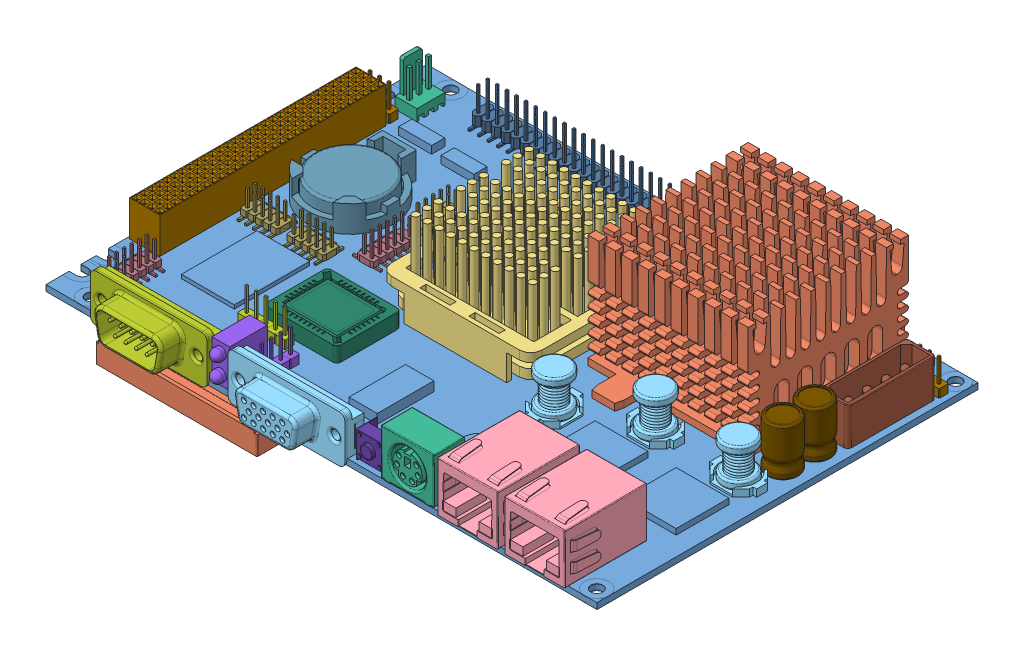
SolidWorks assembly User Library-pc emb ecm-3714 ddm, configuration Default. Lengths in mm.
Overall size (146.04 41.8 107.5).
36 component instances, 27 part files, 103 mates.
Components (placement in the parent):
- User Library-pc emb ecm-3714 ddm_Base CI PC EMB ECM-3714-1: User Library-pc emb ecm-3714 ddm_Base CI PC EMB ECM-3714 [Default] at (-116.1738 3.3292 -30.5336) size (146.04 5.8 101)
- User Library-pc emb ecm-3714 ddm_Disipador aluminio PC DDM-1: User Library-pc emb ecm-3714 ddm_Disipador aluminio PC DDM [Default] at (-2.7838 6.6292 -2.2836) x (0 0 -1) z (1 0 0) size (56.3 30 42.5)
- User Library-pc emb ecm-3714 ddm_Disipador plastico PC DDM-1: User Library-pc emb ecm-3714 ddm_Disipador plastico PC DDM [Default] at (-46.1738 4.9292 11.9664) x (0 0 1) z (-1 0 0) size (40 21.6 41.6)
- User Library-pc emb ecm-3714 ddm_Conector Ethernet PC DDM-1: User Library-pc emb ecm-3714 ddm_Conector Ethernet PC DDM [Default] at (14.6462 5.2292 71.7664) x (-1 0 0) z (0 0 -1) size (18.29 14.35 21.8)
- User Library-pc emb ecm-3714 ddm_Conector Ethernet PC DDM-2: User Library-pc emb ecm-3714 ddm_Conector Ethernet PC DDM [Default] at (-3.1438 5.2292 71.7664) x (-1 0 0) z (0 0 -1) size (18.29 14.35 21.8)
- User Library-pc emb ecm-3714 ddm_Conector VGA PC DDM-1: User Library-pc emb ecm-3714 ddm_Conector VGA PC DDM [Default] at (-51.7338 9.0792 70.6664) size (31 12.5 10.8)
- User Library-pc emb ecm-3714 ddm_Conector raton PC DDM-1: User Library-pc emb ecm-3714 ddm_Conector raton PC DDM [Default] at (-12.6538 5.2292 71.1664) x (-1 0 0) z (0 0 -1) size (14 12.6 8.3)
- User Library-pc emb ecm-3714 ddm_Conector Serial PC DDM-1: User Library-pc emb ecm-3714 ddm_Conector Serial PC DDM [Default] at (-88.2338 9.0792 70.6664) size (31 12.5 10.8)
- User Library-pc emb ecm-3714 ddm_Leds PC DDM-1: User Library-pc emb ecm-3714 ddm_Leds PC DDM [Default] at (-72.2138 4.9292 60.4664) size (4.7 10 12.4)
- User Library-pc emb ecm-3714 ddm_Conector PC104 PCEMB DDM-1: User Library-pc emb ecm-3714 ddm_Conector PC104 PCEMB DDM [Default] at (-115.5338 4.9292 48.9264) size (8 9.5 60)
- User Library-pc emb ecm-3714 ddm_Conector 20x2 PCEMB DDM-1: User Library-pc emb ecm-3714 ddm_Conector 20x2 PCEMB DDM [Default] at (-95.5938 4.9292 -23.0136) size (50.56 9.5 7.5)
- User Library-pc emb ecm-3714 ddm_Conector pwr PCEMB DDM-1: User Library-pc emb ecm-3714 ddm_Conector pwr PCEMB DDM [Default] at (24.0662 3.9292 -9.5836) size (8 10 23.5)
- User Library-pc emb ecm-3714 ddm_Conector 5x2 paso 2 PCEMB DDM-1: User Library-pc emb ecm-3714 ddm_Conector 5x2 paso 2 PCEMB DDM [Default] at (-105.4338 4.9292 28.2764) size (9.9 6.5 7.5)
- User Library-pc emb ecm-3714 ddm_Conector 5x2 paso 2 PCEMB DDM-2: User Library-pc emb ecm-3714 ddm_Conector 5x2 paso 2 PCEMB DDM [Default] at (-93.2438 4.9292 28.1564) size (9.9 6.5 7.5)
- User Library-pc emb ecm-3714 ddm_Conector 5x2 paso 2 PCEMB DDM-3: User Library-pc emb ecm-3714 ddm_Conector 5x2 paso 2 PCEMB DDM [Default] at (-79.3238 4.9292 0.6864) x (0 0 1) z (-1 0 0) size (9.9 6.5 7.5)
- User Library-pc emb ecm-3714 ddm_Conector 6x2 paso 2 PCEMB DDM-1: User Library-pc emb ecm-3714 ddm_Conector 6x2 paso 2 PCEMB DDM [Default] at (-76.8238 4.9292 23.3764) x (0 0 -1) z (1 0 0) size (11.9 6.5 7.5)
- User Library-pc emb ecm-3714 ddm_Conector 6x2 paso 2 PCEMB DDM-2: User Library-pc emb ecm-3714 ddm_Conector 6x2 paso 2 PCEMB DDM [Default] at (-105.5238 4.9292 62.3664) x (0 0 -1) z (1 0 0) size (11.9 6.5 7.5)
- User Library-pc emb ecm-3714 ddm_Pila PCEMB DDM-1: User Library-pc emb ecm-3714 ddm_Pila PCEMB DDM [Default] at (-95.4575 4.9292 10.4664) x (-1 0 0) z (0 0 -1) size (23 7 24.5)
- User Library-pc emb ecm-3714 ddm_Integrado BIOS PCEMB DDM-1: User Library-pc emb ecm-3714 ddm_Integrado BIOS PCEMB DDM [Default] at (-69.0238 4.9292 41.7664) x (0 0 1) z (-1 0 0) size (17 4 19.5)
- User Library-pc emb ecm-3714 ddm_Conector SATA PCEMB DDM-1: User Library-pc emb ecm-3714 ddm_Conector SATA PCEMB DDM [Default] at (-33.1138 4.9292 -27.8036) size (17 8.4 4)
- User Library-pc emb ecm-3714 ddm_Conector SATA PCEMB DDM-2: User Library-pc emb ecm-3714 ddm_Conector SATA PCEMB DDM [Default] at (-15.5838 4.9292 -27.8036) size (17 8.4 4)
- User Library-pc emb ecm-3714 ddm_Pulsador reset PCEMB DDM-1: User Library-pc emb ecm-3714 ddm_Pulsador reset PCEMB DDM [Default] at (-31.3438 8.7792 69.4664) size (7 7.1 6.3)
- User Library-pc emb ecm-3714 ddm_Condensador PCEMB DDM-1: User Library-pc emb ecm-3714 ddm_Condensador PCEMB DDM [Default] at (23.8662 4.9292 6.701) x (0 0 -1) z (1 0 0) size (8.2 12.5 8.2)
- User Library-pc emb ecm-3714 ddm_Condensador PCEMB DDM-2: User Library-pc emb ecm-3714 ddm_Condensador PCEMB DDM [Default] at (23.6726 4.9292 15.0035) size (8.2 12.5 8.2)
- User Library-pc emb ecm-3714 ddm_Conector CF PCEMB DDM-1: User Library-pc emb ecm-3714 ddm_Conector CF PCEMB DDM [Default] at (-78.6338 4.7292 29.4564) x (-1 0 0) z (0 0 1) size (48 8.5 35)
- User Library-pc emb ecm-3714 ddm_Tarjeta compact flash II DDM-1: User Library-pc emb ecm-3714 ddm_Tarjeta compact flash II DDM [Default] at (-78.6338 -1.1708 37.0564) x (-1 0 0) z (0 0 1) size (42.8 5.65 36.4)
- User Library-pc emb ecm-3714 ddm_Conector Memoria RAM DEIDE - 2Rev3DOCDD3-1: User Library-pc emb ecm-3714 ddm_Conector Memoria RAM DEIDE - 2Rev3DOCDD3 [Default] at (-67.4938 3.3292 -13.5336) x (1 0 0) z (0 0 -1) size (71 5.5 9)
- User Library-pc emb ecm-3714 ddm_SODIMM Memoria RAM DDM-1: User Library-pc emb ecm-3714 ddm_SODIMM Memoria RAM DDM [Default] at (-67.6518 -0.2708 18.4664) x (-1 0 0) z (0 0 1) size (67.7 3 31.8)
- User Library-pc emb ecm-3714 ddm_Componente NN PCEMB DDM-1: User Library-pc emb ecm-3714 ddm_Componente NN PCEMB DDM [Default] at (20.6162 4.9292 23.6664) size (12.5 10.7 9.2)
- User Library-pc emb ecm-3714 ddm_Componente NN PCEMB DDM-2: User Library-pc emb ecm-3714 ddm_Componente NN PCEMB DDM [Default] at (-1.3838 4.9292 23.6664) size (12.5 10.7 9.2)
- User Library-pc emb ecm-3714 ddm_Componente NN PCEMB DDM-3: User Library-pc emb ecm-3714 ddm_Componente NN PCEMB DDM [Default] at (-19.4338 4.9292 32.5164) x (0 0 -1) z (1 0 0) size (12.5 10.7 9.2)
- User Library-pc emb ecm-3714 ddm_Conector 3 pins PCEMB DDM-1: User Library-pc emb ecm-3714 ddm_Conector 3 pins PCEMB DDM [Default] at (-104.3838 4.9292 -16.0636) x (0 0 -1) z (1 0 0) size (7.5 11.5 5.8)
- User Library-pc emb ecm-3714 ddm_Conector 5x1 PCEMB DDM-1: User Library-pc emb ecm-3714 ddm_Conector 5x1 PCEMB DDM [Default] at (-81.1938 4.9292 52.7364) size (12.7 8.5 2.54)
- User Library-pc emb ecm-3714 ddm_Conector 4x1 PCEMB DDM-1: User Library-pc emb ecm-3714 ddm_Conector 4x1 PCEMB DDM [Default] at (-65.8738 4.9292 55.9864) x (0 0 1) z (-1 0 0) size (10.16 8.5 2.54)
- User Library-pc emb ecm-3714 ddm_Conector 3x1 PCEMB DDM-1: User Library-pc emb ecm-3714 ddm_Conector 3x1 PCEMB DDM [Default] at (-114.1338 4.9292 -12.8536) size (7.62 8.5 2.54)
- User Library-pc emb ecm-3714 ddm_Conector 3x1 PCEMB DDM-2: User Library-pc emb ecm-3714 ddm_Conector 3x1 PCEMB DDM [Default] at (21.7562 4.9292 -22.7536) size (7.62 8.5 2.54)
Mates (geometry in assembly coordinates):
- Distancia1: distance = 31.7 mm aligned: plane of User Library-pc emb ecm-3714 ddm_Base CI PC EMB ECM-3714-1 through (-114.5338 4.9292 -18.1136) normal (0 1 0); plane of User Library-pc emb ecm-3714 ddm_Disipador aluminio PC DDM-1 through (18.4662 36.6292 18.9664) normal (0 1 0)
- Distancia2: distance = 7 mm aligned: plane of User Library-pc emb ecm-3714 ddm_Base CI PC EMB ECM-3714-1 through (-116.1738 4.9292 -30.5336) normal (0 0 -1); plane of User Library-pc emb ecm-3714 ddm_Disipador aluminio PC DDM-1 through (-24.0338 36.6292 -23.5336) normal (0 0 -1)
- Distancia3: distance = 11.4 mm aligned: plane of User Library-pc emb ecm-3714 ddm_Base CI PC EMB ECM-3714-1 through (29.8662 4.9292 -30.5336) normal (1 0 0); plane of User Library-pc emb ecm-3714 ddm_Disipador aluminio PC DDM-1 through (18.4662 36.6292 18.9664) normal (1 0 0)
- Coincidente1: coincident anti-aligned: plane of User Library-pc emb ecm-3714 ddm_Base CI PC EMB ECM-3714-1 through (-114.5338 4.9292 -18.1136) normal (0 1 0); plane of User Library-pc emb ecm-3714 ddm_Disipador plastico PC DDM-1 through (-66.1838 4.9292 10.2564) normal (0 -1 0)
- Distancia4: distance = 22.5 mm aligned: plane of User Library-pc emb ecm-3714 ddm_Base CI PC EMB ECM-3714-1 through (-116.1738 4.9292 -30.5336) normal (0 0 -1); plane of User Library-pc emb ecm-3714 ddm_Disipador plastico PC DDM-1 through (-26.1738 14.1292 -8.0336) normal (0 0 -1)
- Distancia5: distance = 50 mm aligned: plane of User Library-pc emb ecm-3714 ddm_Base CI PC EMB ECM-3714-1 through (-116.1738 4.9292 -16.5136) normal (-1 0 0); plane of User Library-pc emb ecm-3714 ddm_Disipador plastico PC DDM-1 through (-66.1738 14.1292 -8.0336) normal (-1 0 0)
- Distancia6: distance = 13.5 mm aligned: plane of User Library-pc emb ecm-3714 ddm_Base CI PC EMB ECM-3714-1 through (-114.5338 4.9292 -18.1136) normal (0 1 0); plane of User Library-pc emb ecm-3714 ddm_Conector Ethernet PC DDM-1 through (22.6462 18.4292 49.9664) normal (0 1 0)
- Distancia7: distance = 1.3 mm aligned: plane of User Library-pc emb ecm-3714 ddm_Base CI PC EMB ECM-3714-1 through (-116.1738 4.9292 70.4664) normal (0 0 1); plane of User Library-pc emb ecm-3714 ddm_Conector Ethernet PC DDM-1 through (22.6462 5.2292 71.7664) normal (0 0 1)
- Distancia8: distance = 122.82 mm aligned: plane of User Library-pc emb ecm-3714 ddm_Base CI PC EMB ECM-3714-1 through (-116.1738 4.9292 -30.5336) normal (-1 0 0); plane of User Library-pc emb ecm-3714 ddm_Conector Ethernet PC DDM-1 through (6.6462 18.4292 49.9664) normal (-1 0 0)
- Coincidente7: coincident aligned: plane of User Library-pc emb ecm-3714 ddm_Conector Ethernet PC DDM-1 through (22.6462 5.2292 71.7664) normal (0 0 1); plane of User Library-pc emb ecm-3714 ddm_Conector Ethernet PC DDM-2 through (4.8562 5.2292 71.7664) normal (0 0 1)
- Coincidente8: coincident aligned: plane of User Library-pc emb ecm-3714 ddm_Conector Ethernet PC DDM-1 through (22.6462 18.4292 49.9664) normal (0 1 0); plane of User Library-pc emb ecm-3714 ddm_Conector Ethernet PC DDM-2 through (4.8562 18.4292 49.9664) normal (0 1 0)
- Distancia9: distance = 105.03 mm aligned: plane of User Library-pc emb ecm-3714 ddm_Base CI PC EMB ECM-3714-1 through (-116.1738 4.9292 64.3464) normal (-1 0 0); plane of User Library-pc emb ecm-3714 ddm_Conector Ethernet PC DDM-2 through (-11.1438 18.4292 49.9664) normal (-1 0 0)
- Distancia11: distance = 12 mm anti-aligned: plane of User Library-pc emb ecm-3714 ddm_Base CI PC EMB ECM-3714-1 through (-114.5338 3.3292 -18.1136) normal (0 -1 0); plane of User Library-pc emb ecm-3714 ddm_Conector VGA PC DDM-1 through (-37.7338 15.3292 66.1664) normal (0 1 0)
- Distancia12: distance = 0.2 mm anti-aligned: plane of User Library-pc emb ecm-3714 ddm_Base CI PC EMB ECM-3714-1 through (-116.1738 4.9292 70.4664) normal (0 0 1); plane of User Library-pc emb ecm-3714 ddm_Conector VGA PC DDM-1 through (-67.2338 2.8292 70.6664) normal (0 0 -1)
- Distancia13: distance = 48.94 mm aligned: plane of User Library-pc emb ecm-3714 ddm_Base CI PC EMB ECM-3714-1 through (-116.1738 4.9292 64.3464) normal (-1 0 0); plane of User Library-pc emb ecm-3714 ddm_Conector VGA PC DDM-1 through (-67.2338 13.8292 66.1664) normal (-1 0 0)
- Distancia14: distance = 14.5 mm anti-aligned: plane of User Library-pc emb ecm-3714 ddm_Base CI PC EMB ECM-3714-1 through (-114.5338 3.3292 -18.1136) normal (0 -1 0); plane of User Library-pc emb ecm-3714 ddm_Conector raton PC DDM-1 through (-12.6538 17.8292 62.8664) normal (0 1 0)
- Coincidente15: coincident aligned: plane of User Library-pc emb ecm-3714 ddm_Conector VGA PC DDM-1 through (-67.2338 2.8292 71.1664) normal (0 0 1); plane of User Library-pc emb ecm-3714 ddm_Conector raton PC DDM-1 through (-12.6538 17.8292 71.1664) normal (0 0 1)
- Distancia15: distance = 89.52 mm aligned: plane of User Library-pc emb ecm-3714 ddm_Base CI PC EMB ECM-3714-1 through (-116.1738 4.9292 64.3464) normal (-1 0 0); plane of User Library-pc emb ecm-3714 ddm_Conector raton PC DDM-1 through (-26.6538 5.2292 62.8664) normal (-1 0 0)
- Coincidente17: coincident aligned: plane of User Library-pc emb ecm-3714 ddm_Conector VGA PC DDM-1 through (-37.7338 15.3292 66.1664) normal (0 1 0); plane of User Library-pc emb ecm-3714 ddm_Conector Serial PC DDM-1 through (-74.2338 15.3292 66.1664) normal (0 1 0)
- Coincidente18: coincident aligned: plane of User Library-pc emb ecm-3714 ddm_Conector VGA PC DDM-1 through (-67.2338 2.8292 71.1664) normal (0 0 1); plane of User Library-pc emb ecm-3714 ddm_Conector Serial PC DDM-1 through (-103.7338 2.8292 71.1664) normal (0 0 1)
- Distancia16: distance = 12.44 mm aligned: plane of User Library-pc emb ecm-3714 ddm_Base CI PC EMB ECM-3714-1 through (-116.1738 4.9292 64.3464) normal (-1 0 0); plane of User Library-pc emb ecm-3714 ddm_Conector Serial PC DDM-1 through (-103.7338 13.8292 66.1664) normal (-1 0 0)
- Distancia17: distance = 11.6 mm anti-aligned: plane of User Library-pc emb ecm-3714 ddm_Leds PC DDM-1 through (-72.2138 14.9292 70.4664) normal (0 1 0); plane of User Library-pc emb ecm-3714 ddm_Base CI PC EMB ECM-3714-1 through (-114.5338 3.3292 -18.1136) normal (0 -1 0)
- Coincidente21: coincident aligned: plane of User Library-pc emb ecm-3714 ddm_Base CI PC EMB ECM-3714-1 through (-116.1738 4.9292 70.4664) normal (0 0 1); plane of User Library-pc emb ecm-3714 ddm_Leds PC DDM-1 through (-72.2138 14.9292 70.4664) normal (0 0 1)
- Distancia18: distance = 43.96 mm aligned: plane of User Library-pc emb ecm-3714 ddm_Base CI PC EMB ECM-3714-1 through (-116.1738 4.9292 64.3464) normal (-1 0 0); plane of User Library-pc emb ecm-3714 ddm_Leds PC DDM-1 through (-72.2138 4.9292 70.4664) normal (-1 0 0)
- Distancia19: distance = 78.46 mm anti-aligned: plane of User Library-pc emb ecm-3714 ddm_Base CI PC EMB ECM-3714-1 through (-116.1738 4.9292 -30.5336) normal (0 0 -1); plane of User Library-pc emb ecm-3714 ddm_Conector PC104 PCEMB DDM-1 through (-115.5338 4.9292 47.9264) normal (0 0 1)
- Distancia20: distance = 7.64 mm anti-aligned: plane of User Library-pc emb ecm-3714 ddm_Base CI PC EMB ECM-3714-1 through (-116.1738 4.9292 -16.5136) normal (-1 0 0); plane of User Library-pc emb ecm-3714 ddm_Conector PC104 PCEMB DDM-1 through (-108.5338 4.9292 48.9264) normal (1 0 0)
- Coincidente25: coincident anti-aligned: plane of User Library-pc emb ecm-3714 ddm_Base CI PC EMB ECM-3714-1 through (-114.5338 4.9292 -18.1136) normal (0 1 0); plane of User Library-pc emb ecm-3714 ddm_Conector PC104 PCEMB DDM-1 through (-115.5338 4.9292 -11.0736) normal (0 -1 0)
- Distancia23: distance = 69.34 mm anti-aligned: plane of User Library-pc emb ecm-3714 ddm_Base CI PC EMB ECM-3714-1 through (-116.1738 4.9292 -30.5336) normal (-1 0 0); plane of User Library-pc emb ecm-3714 ddm_Conector 20x2 PCEMB DDM-1 through (-46.8338 14.4292 -23.0136) normal (1 0 0)
- Distancia24: distance = 4.48 mm aligned: plane of User Library-pc emb ecm-3714 ddm_Base CI PC EMB ECM-3714-1 through (-116.1738 4.9292 -30.5336) normal (0 0 -1); plane of User Library-pc emb ecm-3714 ddm_Conector 20x2 PCEMB DDM-1 through (-47.3338 14.4292 -26.0536) normal (0 0 -1)
- Coincidente31: coincident anti-aligned: plane of User Library-pc emb ecm-3714 ddm_Base CI PC EMB ECM-3714-1 through (-114.5338 4.9292 -18.1136) normal (0 1 0); plane of User Library-pc emb ecm-3714 ddm_Conector 20x2 PCEMB DDM-1 through (-95.5938 4.9292 -23.5136) normal (0 -1 0)
- Coincidente32: coincident anti-aligned: plane of User Library-pc emb ecm-3714 ddm_Base CI PC EMB ECM-3714-1 through (-114.5338 4.9292 -18.1136) normal (0 1 0); plane of User Library-pc emb ecm-3714 ddm_Conector pwr PCEMB DDM-1 through (21.0662 4.9292 1.1664) normal (0 -1 0)
- Distancia25: distance = 1.8 mm aligned: plane of User Library-pc emb ecm-3714 ddm_Base CI PC EMB ECM-3714-1 through (29.8662 4.9292 -30.5336) normal (1 0 0); plane of User Library-pc emb ecm-3714 ddm_Conector pwr PCEMB DDM-1 through (28.0662 5.4292 -20.3336) normal (1 0 0)
- Distancia26: distance = 9.2 mm aligned: plane of User Library-pc emb ecm-3714 ddm_Base CI PC EMB ECM-3714-1 through (-116.1738 4.9292 -30.5336) normal (0 0 -1); plane of User Library-pc emb ecm-3714 ddm_Conector pwr PCEMB DDM-1 through (21.0662 5.4292 -21.3336) normal (0 0 -1)
- Distancia27: distance = 10.74 mm aligned: plane of User Library-pc emb ecm-3714 ddm_Base CI PC EMB ECM-3714-1 through (-116.1738 4.9292 -16.5136) normal (-1 0 0); plane of User Library-pc emb ecm-3714 ddm_Conector 5x2 paso 2 PCEMB DDM-1 through (-105.4338 11.4292 28.2764) normal (-1 0 0)
- Distancia28: distance = 58.81 mm anti-aligned: plane of User Library-pc emb ecm-3714 ddm_Base CI PC EMB ECM-3714-1 through (-116.1738 4.9292 -30.5336) normal (0 0 -1); plane of User Library-pc emb ecm-3714 ddm_Conector 5x2 paso 2 PCEMB DDM-1 through (-105.4338 11.4292 28.2764) normal (0 0 1)
- Coincidente37: coincident anti-aligned: plane of User Library-pc emb ecm-3714 ddm_Base CI PC EMB ECM-3714-1 through (-114.5338 4.9292 -18.1136) normal (0 1 0); plane of User Library-pc emb ecm-3714 ddm_Conector 5x2 paso 2 PCEMB DDM-1 through (-97.4338 4.9292 27.7764) normal (0 -1 0)
- Distancia29: distance = 22.93 mm aligned: plane of User Library-pc emb ecm-3714 ddm_Base CI PC EMB ECM-3714-1 through (-116.1738 4.9292 -16.5136) normal (-1 0 0); plane of User Library-pc emb ecm-3714 ddm_Conector 5x2 paso 2 PCEMB DDM-2 through (-93.2438 11.4292 28.1564) normal (-1 0 0)
- Distancia30: distance = 58.69 mm anti-aligned: plane of User Library-pc emb ecm-3714 ddm_Base CI PC EMB ECM-3714-1 through (-116.1738 4.9292 -30.5336) normal (0 0 -1); plane of User Library-pc emb ecm-3714 ddm_Conector 5x2 paso 2 PCEMB DDM-2 through (-93.2438 11.4292 28.1564) normal (0 0 1)
- Coincidente40: coincident anti-aligned: plane of User Library-pc emb ecm-3714 ddm_Base CI PC EMB ECM-3714-1 through (-114.5338 4.9292 -18.1136) normal (0 1 0); plane of User Library-pc emb ecm-3714 ddm_Conector 5x2 paso 2 PCEMB DDM-2 through (-93.2438 4.9292 27.6564) normal (0 -1 0)
- Distancia31: distance = 36.85 mm aligned: plane of User Library-pc emb ecm-3714 ddm_Base CI PC EMB ECM-3714-1 through (-116.1738 4.9292 -16.5136) normal (-1 0 0); plane of User Library-pc emb ecm-3714 ddm_Conector 5x2 paso 2 PCEMB DDM-3 through (-79.3238 11.4292 0.6864) normal (-1 0 0)
- Distancia32: distance = 31.22 mm aligned: plane of User Library-pc emb ecm-3714 ddm_Base CI PC EMB ECM-3714-1 through (-116.1738 4.9292 -30.5336) normal (0 0 -1); plane of User Library-pc emb ecm-3714 ddm_Conector 5x2 paso 2 PCEMB DDM-3 through (-79.3238 11.4292 0.6864) normal (0 0 -1)
- Coincidente43: coincident anti-aligned: plane of User Library-pc emb ecm-3714 ddm_Base CI PC EMB ECM-3714-1 through (-114.5338 4.9292 -18.1136) normal (0 1 0); plane of User Library-pc emb ecm-3714 ddm_Conector 5x2 paso 2 PCEMB DDM-3 through (-78.8238 4.9292 6.6864) normal (0 -1 0)
- Coincidente44: coincident aligned: plane of User Library-pc emb ecm-3714 ddm_Conector 5x2 paso 2 PCEMB DDM-3 through (-75.9238 6.9292 9.672) normal (1 0 0); plane of User Library-pc emb ecm-3714 ddm_Conector 6x2 paso 2 PCEMB DDM-1 through (-75.9238 6.9292 14.3907) normal (1 0 0)
- Coincidente45: coincident aligned: plane of User Library-pc emb ecm-3714 ddm_Conector 5x2 paso 2 PCEMB DDM-3 through (-80.2238 6.9292 7.0486) normal (0 1 0); plane of User Library-pc emb ecm-3714 ddm_Conector 6x2 paso 2 PCEMB DDM-1 through (-75.9238 6.9292 15.0142) normal (0 1 0)
- Distancia33: distance = 43.41 mm aligned: plane of User Library-pc emb ecm-3714 ddm_Base CI PC EMB ECM-3714-1 through (-116.1738 4.9292 -30.5336) normal (0 0 -1); plane of User Library-pc emb ecm-3714 ddm_Conector 6x2 paso 2 PCEMB DDM-1 through (-74.5738 5.4292 12.8764) normal (0 0 -1)
- Distancia34: distance = 10.65 mm anti-aligned: plane of User Library-pc emb ecm-3714 ddm_Base CI PC EMB ECM-3714-1 through (-116.1738 4.9292 64.3464) normal (-1 0 0); plane of User Library-pc emb ecm-3714 ddm_Conector 6x2 paso 2 PCEMB DDM-2 through (-105.5238 11.4292 62.3664) normal (1 0 0)
- Coincidente48: coincident anti-aligned: plane of User Library-pc emb ecm-3714 ddm_Base CI PC EMB ECM-3714-1 through (-114.5338 4.9292 -18.1136) normal (0 1 0); plane of User Library-pc emb ecm-3714 ddm_Conector 6x2 paso 2 PCEMB DDM-2 through (-106.0238 4.9292 62.3664) normal (0 -1 0)
- Distancia35: distance = 7.4 mm aligned: plane of User Library-pc emb ecm-3714 ddm_Base CI PC EMB ECM-3714-1 through (-116.1738 4.9292 70.4664) normal (0 0 1); plane of User Library-pc emb ecm-3714 ddm_Conector 6x2 paso 2 PCEMB DDM-2 through (-108.1238 6.9292 63.0664) normal (0 0 1)
- Coincidente50: coincident anti-aligned: plane of User Library-pc emb ecm-3714 ddm_Base CI PC EMB ECM-3714-1 through (-114.5338 4.9292 -18.1136) normal (0 1 0); plane of User Library-pc emb ecm-3714 ddm_Pila PCEMB DDM-1 through (-95.4575 4.9292 10.4664) normal (0 -1 0)
- Distancia36: distance = 28 mm aligned: plane of User Library-pc emb ecm-3714 ddm_Base CI PC EMB ECM-3714-1 through (-116.1738 4.9292 -30.5336) normal (0 0 -1); plane of User Library-pc emb ecm-3714 ddm_Pila PCEMB DDM-1 through (-99.9575 11.9292 -2.5336) normal (0 0 -1)
- Distancia37: distance = 26.1566 mm aligned: plane of User Library-pc emb ecm-3714 ddm_Base CI PC EMB ECM-3714-1 through (-116.1738 4.9292 -16.5136) normal (-1 0 0); plane of User Library-pc emb ecm-3714 ddm_Pila PCEMB DDM-1 through (-90.0172 7.9292 16.2445) normal (-1 0 0)
- Distancia38: distance = 20.2 mm aligned: plane of User Library-pc emb ecm-3714 ddm_Base CI PC EMB ECM-3714-1 through (-116.1738 4.9292 70.4664) normal (0 0 1); plane of User Library-pc emb ecm-3714 ddm_Integrado BIOS PCEMB DDM-1 through (-60.2738 8.9292 50.2664) normal (0 0 1)
- Distancia39: distance = 37.4 mm aligned: plane of User Library-pc emb ecm-3714 ddm_Base CI PC EMB ECM-3714-1 through (-116.1738 4.9292 -16.5136) normal (-1 0 0); plane of User Library-pc emb ecm-3714 ddm_Integrado BIOS PCEMB DDM-1 through (-78.7738 8.9292 34.2664) normal (-1 0 0)
- Coincidente55: coincident anti-aligned: plane of User Library-pc emb ecm-3714 ddm_Base CI PC EMB ECM-3714-1 through (-114.5338 4.9292 -18.1136) normal (0 1 0); plane of User Library-pc emb ecm-3714 ddm_Integrado BIOS PCEMB DDM-1 through (-60.2738 4.9292 34.2664) normal (0 -1 0)
- Distancia40: distance = 4.73 mm anti-aligned: plane of User Library-pc emb ecm-3714 ddm_Base CI PC EMB ECM-3714-1 through (-116.1738 4.9292 -30.5336) normal (0 0 -1); plane of User Library-pc emb ecm-3714 ddm_Conector SATA PCEMB DDM-1 through (-41.6138 13.3292 -25.8036) normal (0 0 1)
- Distancia41: distance = 74.56 mm aligned: plane of User Library-pc emb ecm-3714 ddm_Base CI PC EMB ECM-3714-1 through (-116.1738 4.9292 -30.5336) normal (-1 0 0); plane of User Library-pc emb ecm-3714 ddm_Conector SATA PCEMB DDM-1 through (-41.6138 13.3292 -29.8036) normal (-1 0 0)
- Coincidente58: coincident anti-aligned: plane of User Library-pc emb ecm-3714 ddm_Base CI PC EMB ECM-3714-1 through (-114.5338 4.9292 -18.1136) normal (0 1 0); plane of User Library-pc emb ecm-3714 ddm_Conector SATA PCEMB DDM-1 through (-41.6138 4.9292 -25.8036) normal (0 -1 0)
- Coincidente59: coincident aligned: plane of User Library-pc emb ecm-3714 ddm_Conector SATA PCEMB DDM-1 through (-41.6138 13.3292 -25.8036) normal (0 0 1); plane of User Library-pc emb ecm-3714 ddm_Conector SATA PCEMB DDM-2 through (-24.0838 13.3292 -25.8036) normal (0 0 1)
- Distancia42: distance = 92.09 mm aligned: plane of User Library-pc emb ecm-3714 ddm_Base CI PC EMB ECM-3714-1 through (-116.1738 4.9292 -30.5336) normal (-1 0 0); plane of User Library-pc emb ecm-3714 ddm_Conector SATA PCEMB DDM-2 through (-24.0838 13.3292 -29.8036) normal (-1 0 0)
- Coincidente61: coincident anti-aligned: plane of User Library-pc emb ecm-3714 ddm_Base CI PC EMB ECM-3714-1 through (-114.5338 4.9292 -18.1136) normal (0 1 0); plane of User Library-pc emb ecm-3714 ddm_Conector SATA PCEMB DDM-2 through (-24.0838 4.9292 -25.8036) normal (0 -1 0)
- Coincidente62: coincident anti-aligned: plane of User Library-pc emb ecm-3714 ddm_Base CI PC EMB ECM-3714-1 through (-114.5338 4.9292 -18.1136) normal (0 1 0); plane of User Library-pc emb ecm-3714 ddm_Pulsador reset PCEMB DDM-1 through (-28.0438 4.9292 64.1664) normal (0 -1 0)
- Distancia43: distance = 81.33 mm aligned: plane of User Library-pc emb ecm-3714 ddm_Base CI PC EMB ECM-3714-1 through (-116.1738 4.9292 64.3464) normal (-1 0 0); plane of User Library-pc emb ecm-3714 ddm_Pulsador reset PCEMB DDM-1 through (-34.8438 12.0292 69.6664) normal (-1 0 0)
- Coincidente64: coincident aligned: plane of User Library-pc emb ecm-3714 ddm_Base CI PC EMB ECM-3714-1 through (-116.1738 4.9292 70.4664) normal (0 0 1); plane of User Library-pc emb ecm-3714 ddm_Pulsador reset PCEMB DDM-1 through (-31.3438 8.7792 70.4664) normal (0 0 1)
- Coincidente65: coincident anti-aligned: plane of User Library-pc emb ecm-3714 ddm_Base CI PC EMB ECM-3714-1 through (-114.5338 4.9292 -18.1136) normal (0 1 0); plane of User Library-pc emb ecm-3714 ddm_Condensador PCEMB DDM-1 through (23.8662 4.9292 6.701) normal (0 -1 0)
- Distancia44: distance = 6 mm aligned: plane of User Library-pc emb ecm-3714 ddm_Base CI PC EMB ECM-3714-1 through (29.8662 4.9292 -30.5336) normal (1 0 0); plane of User Library-pc emb ecm-3714 ddm_Condensador PCEMB DDM-1 through (23.8662 4.9292 6.701) normal (1 0 0)
- Distancia45: distance = 37.2346 mm aligned: plane of User Library-pc emb ecm-3714 ddm_Base CI PC EMB ECM-3714-1 through (-116.1738 4.9292 -30.5336) normal (0 0 -1); plane of User Library-pc emb ecm-3714 ddm_Condensador PCEMB DDM-1 through (23.8662 4.9292 6.701) normal (0 0 -1)
- Coincidente68: coincident aligned: plane of User Library-pc emb ecm-3714 ddm_Condensador PCEMB DDM-1 through (23.8662 17.2292 6.701) normal (0 1 0); plane of User Library-pc emb ecm-3714 ddm_Condensador PCEMB DDM-2 through (23.6726 17.2292 15.0035) normal (0 1 0)
- Coincidente69: coincident anti-aligned: plane of User Library-pc emb ecm-3714 ddm_Base CI PC EMB ECM-3714-1 through (-114.5338 3.3292 -18.1136) normal (0 -1 0); plane of User Library-pc emb ecm-3714 ddm_Conector CF PCEMB DDM-1 through (-44.6338 3.3292 25.0912) normal (0 1 0)
- Concéntrica1: concentric aligned: circle of User Library-pc emb ecm-3714 ddm_Base CI PC EMB ECM-3714-1; circle of User Library-pc emb ecm-3714 ddm_Conector CF PCEMB DDM-1
- Concéntrica2: concentric aligned: circle of User Library-pc emb ecm-3714 ddm_Base CI PC EMB ECM-3714-1; circle of User Library-pc emb ecm-3714 ddm_Conector CF PCEMB DDM-1
- Coincidente72: coincident anti-aligned: plane of User Library-pc emb ecm-3714 ddm_Conector CF PCEMB DDM-1 through (-94.7338 33.1595 37.0564) normal (0 0 1); plane of User Library-pc emb ecm-3714 ddm_Tarjeta compact flash II DDM-1 through (-57.2338 1.3292 37.0564) normal (0 0 -1)
- Distancia47: distance = 0.2 mm anti-aligned: plane of User Library-pc emb ecm-3714 ddm_Conector CF PCEMB DDM-1 through (-58.0338 -5.1708 64.4564) normal (-1 0 0); plane of User Library-pc emb ecm-3714 ddm_Tarjeta compact flash II DDM-1 through (-58.2338 -1.9208 63.0564) normal (1 0 0)
- Coincidente76: coincident anti-aligned: plane of User Library-pc emb ecm-3714 ddm_Conector CF PCEMB DDM-1 through (-100.2338 -1.9208 36.6564) normal (0 -1 0); plane of User Library-pc emb ecm-3714 ddm_Tarjeta compact flash II DDM-1 through (-100.5798 -1.9208 63.0564) normal (0 1 0)
- Coincidente77: coincident anti-aligned: plane of User Library-pc emb ecm-3714 ddm_Base CI PC EMB ECM-3714-1 through (-114.5338 3.3292 -18.1136) normal (0 -1 0); plane of User Library-pc emb ecm-3714 ddm_Conector Memoria RAM DEIDE - 2Rev3DOCDD3-1 through (-102.9938 3.3292 -17.0336) normal (0 1 0)
- Distancia48: distance = 20.5 mm anti-aligned: plane of User Library-pc emb ecm-3714 ddm_Base CI PC EMB ECM-3714-1 through (-116.1738 4.9292 -30.5336) normal (0 0 -1); plane of User Library-pc emb ecm-3714 ddm_Conector Memoria RAM DEIDE - 2Rev3DOCDD3-1 through (-102.9938 -2.1708 -10.0336) normal (0 0 1)
- Distancia49: distance = 48.68 mm anti-aligned: plane of User Library-pc emb ecm-3714 ddm_Base CI PC EMB ECM-3714-1 through (-116.1738 4.9292 -30.5336) normal (-1 0 0); plane of User Library-pc emb ecm-3714 ddm_Conector Memoria RAM DEIDE - 2Rev3DOCDD3-1
- Distancia50: distance = 5.6 mm aligned: plane of User Library-pc emb ecm-3714 ddm_Base CI PC EMB ECM-3714-1 through (-114.5338 3.3292 -18.1136) normal (0 -1 0); plane of User Library-pc emb ecm-3714 ddm_SODIMM Memoria RAM DDM-1 through (-50.1518 -2.2708 16.4664) normal (0 -1 0)
- Distancia51: distance = 52 mm aligned: plane of User Library-pc emb ecm-3714 ddm_Base CI PC EMB ECM-3714-1 through (-116.1738 4.9292 70.4664) normal (0 0 1); plane of User Library-pc emb ecm-3714 ddm_SODIMM Memoria RAM DDM-1 through (-33.8018 -1.2708 18.4664) normal (0 0 1)
- Distancia52: distance = 14.672 mm aligned: plane of User Library-pc emb ecm-3714 ddm_Base CI PC EMB ECM-3714-1 through (-116.1738 4.9292 -16.5136) normal (-1 0 0); plane of User Library-pc emb ecm-3714 ddm_SODIMM Memoria RAM DDM-1 through (-101.5018 -1.2708 -13.3336) normal (-1 0 0)
- Distancia53: distance = 0.1 mm anti-aligned: plane of User Library-pc emb ecm-3714 ddm_Disipador aluminio PC DDM-1 through (-24.0338 36.6292 18.9664) normal (0 0 1); plane of User Library-pc emb ecm-3714 ddm_Componente NN PCEMB DDM-1 through (15.3662 6.8292 19.0664) normal (0 0 -1)
- Coincidente84: coincident anti-aligned: plane of User Library-pc emb ecm-3714 ddm_Base CI PC EMB ECM-3714-1 through (-114.5338 4.9292 -18.1136) normal (0 1 0); plane of User Library-pc emb ecm-3714 ddm_Componente NN PCEMB DDM-1 through (15.3662 4.9292 28.2664) normal (0 -1 0)
- Distancia54: distance = 3 mm aligned: plane of User Library-pc emb ecm-3714 ddm_Base CI PC EMB ECM-3714-1 through (29.8662 4.9292 -30.5336) normal (1 0 0); plane of User Library-pc emb ecm-3714 ddm_Componente NN PCEMB DDM-1 through (26.8662 4.9292 22.2164) normal (1 0 0)
- Coincidente86: coincident aligned: plane of User Library-pc emb ecm-3714 ddm_Componente NN PCEMB DDM-1 through (20.6162 15.6292 23.6664) normal (0 1 0); plane of User Library-pc emb ecm-3714 ddm_Componente NN PCEMB DDM-2 through (-1.3838 15.6292 23.6664) normal (0 1 0)
- Coincidente87: coincident aligned: plane of User Library-pc emb ecm-3714 ddm_Componente NN PCEMB DDM-1 through (15.3662 6.8292 28.2664) normal (0 0 1); plane of User Library-pc emb ecm-3714 ddm_Componente NN PCEMB DDM-2 through (-6.6338 6.8292 28.2664) normal (0 0 1)
- Distancia55: distance = 9.5 mm anti-aligned: plane of User Library-pc emb ecm-3714 ddm_Componente NN PCEMB DDM-1 through (14.3662 4.9292 22.2164) normal (-1 0 0); plane of User Library-pc emb ecm-3714 ddm_Componente NN PCEMB DDM-2 through (4.8662 4.9292 22.2164) normal (1 0 0)
- Coincidente89: coincident aligned: plane of User Library-pc emb ecm-3714 ddm_Componente NN PCEMB DDM-2 through (-1.3838 15.6292 23.6664) normal (0 1 0); plane of User Library-pc emb ecm-3714 ddm_Componente NN PCEMB DDM-3 through (-19.4338 15.6292 32.5164) normal (0 1 0)
- Distancia56: distance = 33 mm aligned: plane of User Library-pc emb ecm-3714 ddm_Conector Ethernet PC DDM-2 through (4.8562 5.2292 71.7664) normal (0 0 1); plane of User Library-pc emb ecm-3714 ddm_Componente NN PCEMB DDM-3 through (-20.8838 4.9292 38.7664) normal (0 0 1)
- Coincidente91: coincident aligned: plane of User Library-pc emb ecm-3714 ddm_Disipador aluminio PC DDM-1 through (-24.0338 36.6292 18.9664) normal (-1 0 0); plane of User Library-pc emb ecm-3714 ddm_Componente NN PCEMB DDM-3 through (-24.0338 6.8292 37.7664) normal (-1 0 0)
- Distancia57: distance = 7.78 mm aligned: plane of User Library-pc emb ecm-3714 ddm_Base CI PC EMB ECM-3714-1 through (-116.1738 4.9292 -30.5336) normal (0 0 -1); plane of User Library-pc emb ecm-3714 ddm_Conector 3 pins PCEMB DDM-1 through (-107.9838 15.4292 -22.7536) normal (0 0 -1)
- Distancia58: distance = 8.19 mm aligned: plane of User Library-pc emb ecm-3714 ddm_Base CI PC EMB ECM-3714-1 through (-116.1738 4.9292 -30.5336) normal (-1 0 0); plane of User Library-pc emb ecm-3714 ddm_Conector 3 pins PCEMB DDM-1 through (-107.9838 15.4292 -21.9536) normal (-1 0 0)
- Coincidente94: coincident anti-aligned: plane of User Library-pc emb ecm-3714 ddm_Base CI PC EMB ECM-3714-1 through (-114.5338 4.9292 -18.1136) normal (0 1 0); plane of User Library-pc emb ecm-3714 ddm_Conector 3 pins PCEMB DDM-1 through (-110.1838 4.9292 -16.0636) normal (0 -1 0)
- Distancia59: distance = 34.98 mm aligned: plane of User Library-pc emb ecm-3714 ddm_Base CI PC EMB ECM-3714-1 through (-116.1738 4.9292 -16.5136) normal (-1 0 0); plane of User Library-pc emb ecm-3714 ddm_Conector 5x1 PCEMB DDM-1 through (-81.1938 13.4292 52.7364) normal (-1 0 0)
- Distancia60: distance = 82.77 mm aligned: plane of User Library-pc emb ecm-3714 ddm_Base CI PC EMB ECM-3714-1 through (-116.1738 4.9292 -30.5336) normal (0 0 -1); plane of User Library-pc emb ecm-3714 ddm_Conector 5x1 PCEMB DDM-1 through (-81.1938 13.4292 52.2364) normal (0 0 -1)
- Distancia61: distance = 50.3 mm aligned: plane of User Library-pc emb ecm-3714 ddm_Base CI PC EMB ECM-3714-1 through (-116.1738 4.9292 -16.5136) normal (-1 0 0); plane of User Library-pc emb ecm-3714 ddm_Conector 4x1 PCEMB DDM-1 through (-65.8738 13.4292 63.6064) normal (-1 0 0)
- Distancia62: distance = 94.14 mm aligned: plane of User Library-pc emb ecm-3714 ddm_Base CI PC EMB ECM-3714-1 through (-116.1738 4.9292 -30.5336) normal (0 0 -1); plane of User Library-pc emb ecm-3714 ddm_Conector 4x1 PCEMB DDM-1 through (-65.8738 13.4292 63.6064) normal (0 0 -1)
- Coincidente100: coincident anti-aligned: plane of User Library-pc emb ecm-3714 ddm_Base CI PC EMB ECM-3714-1 through (-114.5338 4.9292 -18.1136) normal (0 1 0); plane of User Library-pc emb ecm-3714 ddm_Conector 4x1 PCEMB DDM-1 through (-64.3538 4.9292 60.0464) normal (0 -1 0)
- Distancia63: distance = 17.18 mm aligned: plane of User Library-pc emb ecm-3714 ddm_Base CI PC EMB ECM-3714-1 through (-116.1738 4.9292 -30.5336) normal (0 0 -1); plane of User Library-pc emb ecm-3714 ddm_Conector 3x1 PCEMB DDM-1 through (-114.1338 13.4292 -13.3536) normal (0 0 -1)
- Distancia64: distance = 2.04 mm aligned: plane of User Library-pc emb ecm-3714 ddm_Base CI PC EMB ECM-3714-1 through (-116.1738 4.9292 -16.5136) normal (-1 0 0); plane of User Library-pc emb ecm-3714 ddm_Conector 3x1 PCEMB DDM-1 through (-114.1338 13.4292 -12.8536) normal (-1 0 0)
- Coincidente103: coincident anti-aligned: plane of User Library-pc emb ecm-3714 ddm_Base CI PC EMB ECM-3714-1 through (-114.5338 4.9292 -18.1136) normal (0 1 0); plane of User Library-pc emb ecm-3714 ddm_Conector 3x1 PCEMB DDM-1 through (-115.1538 4.9292 -14.3736) normal (0 -1 0)
- Coincidente104: coincident anti-aligned: plane of User Library-pc emb ecm-3714 ddm_Base CI PC EMB ECM-3714-1 through (-114.5338 4.9292 -18.1136) normal (0 1 0); plane of User Library-pc emb ecm-3714 ddm_Conector 5x1 PCEMB DDM-1 through (-82.2138 4.9292 51.2164) normal (0 -1 0)
- Distancia65: distance = 7.28 mm aligned: plane of User Library-pc emb ecm-3714 ddm_Base CI PC EMB ECM-3714-1 through (-116.1738 4.9292 -30.5336) normal (0 0 -1); plane of User Library-pc emb ecm-3714 ddm_Conector 3x1 PCEMB DDM-2 through (24.2962 13.4292 -23.2536) normal (0 0 -1)
- Distancia66: distance = 143.01 mm aligned: plane of User Library-pc emb ecm-3714 ddm_Base CI PC EMB ECM-3714-1 through (-116.1738 4.9292 -30.5336) normal (-1 0 0); plane of User Library-pc emb ecm-3714 ddm_Conector 3x1 PCEMB DDM-2 through (26.8362 13.4292 -22.7536) normal (-1 0 0)
- Coincidente107: coincident anti-aligned: plane of User Library-pc emb ecm-3714 ddm_Base CI PC EMB ECM-3714-1 through (-114.5338 4.9292 -18.1136) normal (0 1 0); plane of User Library-pc emb ecm-3714 ddm_Conector 3x1 PCEMB DDM-2 through (25.8162 4.9292 -24.2736) normal (0 -1 0)
